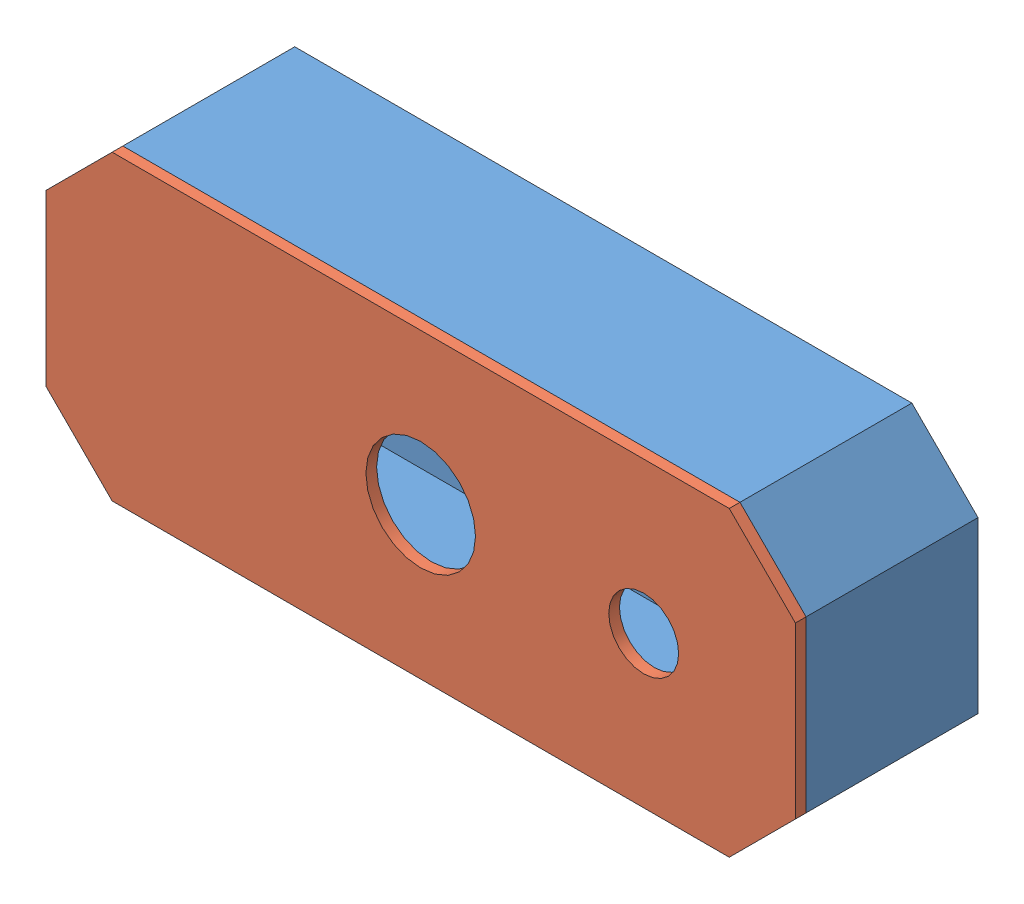
SolidWorks assembly Assem1, configuration Default. Lengths in mm.
Overall size (56.08 22.61 13.66).
2 component instances, 2 part files, 3 mates.
Components (placement in the parent):
- Case Bottom-1: Case Bottom [Default] at (12.4679 40.6639 35.8809) size (56.08 22.61 12.87)
- Case top-1: Case top [Default] at (12.4679 40.6639 49.5459) x (-1 0 0) z (0 0 -1) size (56.08 22.61 5.56)
Mates (geometry in assembly coordinates):
- Coincident1: coincident anti-aligned: plane of Case Bottom-1 through (12.4679 40.6639 48.7459) normal (0 0 1); plane of Case top-1 through (12.4679 40.6639 48.7459) normal (0 0 -1)
- Coincident2: coincident aligned: plane of Case Bottom-1 through (40.5094 29.361 36.6809) normal (1 0 0); plane of Case top-1 through (40.5094 29.361 48.7459) normal (1 0 0)
- Coincident3: coincident aligned: plane of Case Bottom-1 through (-15.5736 51.9668 36.6809) normal (0 1 0); plane of Case top-1 through (40.5094 51.9668 48.7459) normal (0 1 0)
